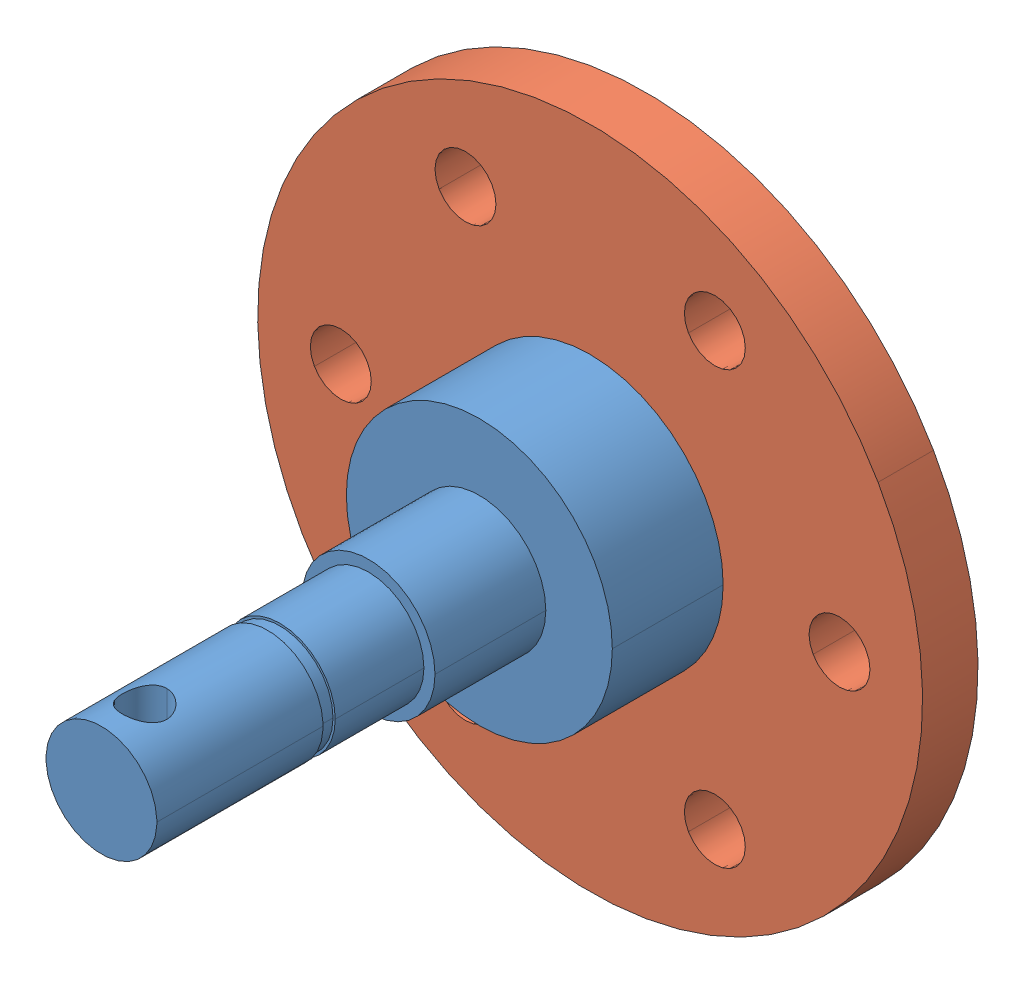
SolidWorks assembly 10mm钢制联轴器, configuration 默认. Lengths in mm.
Overall size (81.96 81.96 49.1).
3 component instances, 2 part files, 0 mates.
Components (placement in the parent):
- 10mm钢制联轴器.STEP-1: 10mm钢制联轴器.STEP [Default] at origin size (81.96 81.96 49.1)
  - __________.STEP-1: __________.STEP [Default] at (3.7664 -0.9677 32.1012) size (24 24 44.1)
  - 3510______ ____2.STEP-1: 3510______ ____2.STEP [Default] at (9.8274 82.7684 22.1012) x (0.5 -0.866025 0) z (0.866025 0.5 0) size (60 5 60)
